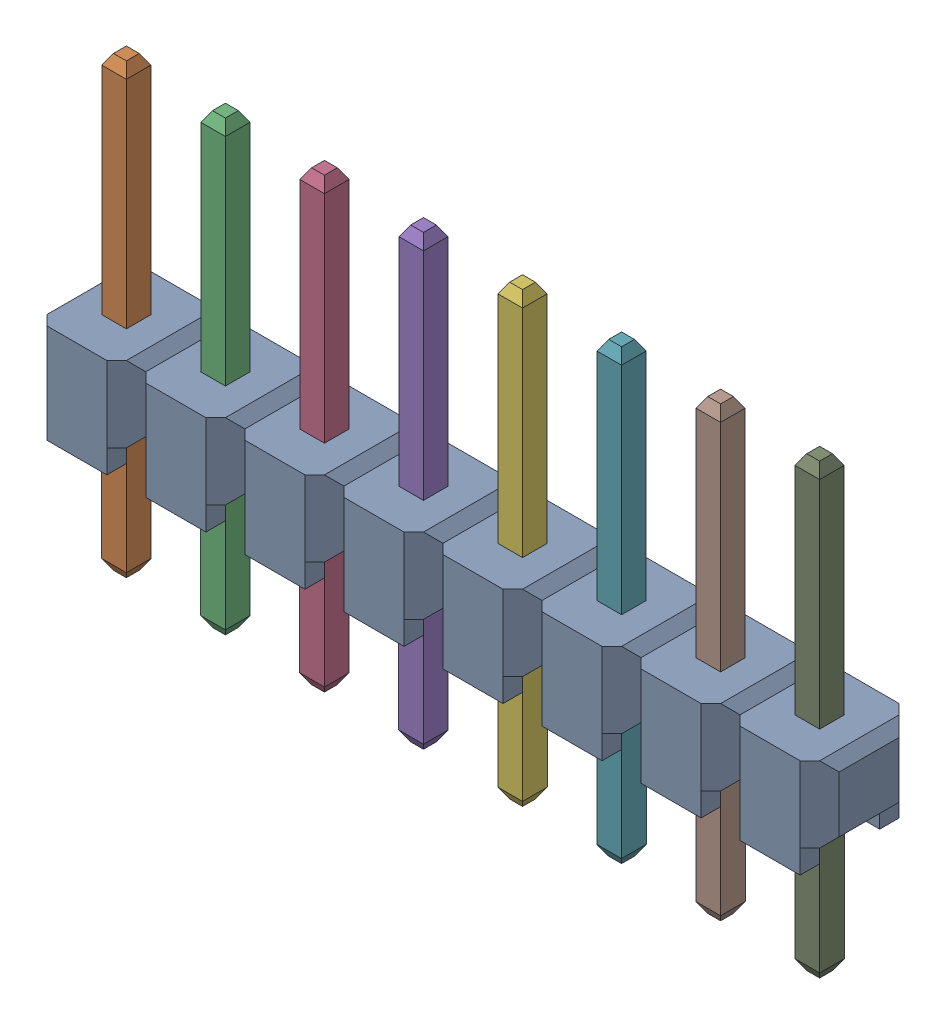
SolidWorks assembly m20-9770842_asm.stp, configuration Default. Lengths in mm.
Overall size (20.32 11.48 2.54).
10 component instances, 2 part files, 0 mates.
Components (placement in the parent):
- M20-977_ASM_2-1: M20-977_ASM_2 [Default] at origin size (20.32 11.48 2.54)
  - M20-977-MOULD-1: M20-977-MOULD [Default] at origin size (20.32 2.54 2.54)
  - M20-977-PIN.5-1: M20-977-PIN.5 [Default] at (2.54 -5.68 0) x (1 0 0) z (0 0 -1) size (0.64 11.48 0.64)
  - M20-977-PIN.5-2: M20-977-PIN.5 [Default] at (5.08 -5.68 0) x (1 0 0) z (0 0 -1) size (0.64 11.48 0.64)
  - M20-977-PIN.5-3: M20-977-PIN.5 [Default] at (7.62 -5.68 0) x (1 0 0) z (0 0 -1) size (0.64 11.48 0.64)
  - M20-977-PIN.5-4: M20-977-PIN.5 [Default] at (10.16 -5.68 0) x (1 0 0) z (0 0 -1) size (0.64 11.48 0.64)
  - M20-977-PIN.5-5: M20-977-PIN.5 [Default] at (12.7 -5.68 0) x (1 0 0) z (0 0 -1) size (0.64 11.48 0.64)
  - M20-977-PIN.5-6: M20-977-PIN.5 [Default] at (15.24 -5.68 0) x (1 0 0) z (0 0 -1) size (0.64 11.48 0.64)
  - M20-977-PIN.5-7: M20-977-PIN.5 [Default] at (17.78 -5.68 0) x (1 0 0) z (0 0 -1) size (0.64 11.48 0.64)
  - M20-977-PIN.5-8: M20-977-PIN.5 [Default] at (20.32 -5.68 0) x (1 0 0) z (0 0 -1) size (0.64 11.48 0.64)
